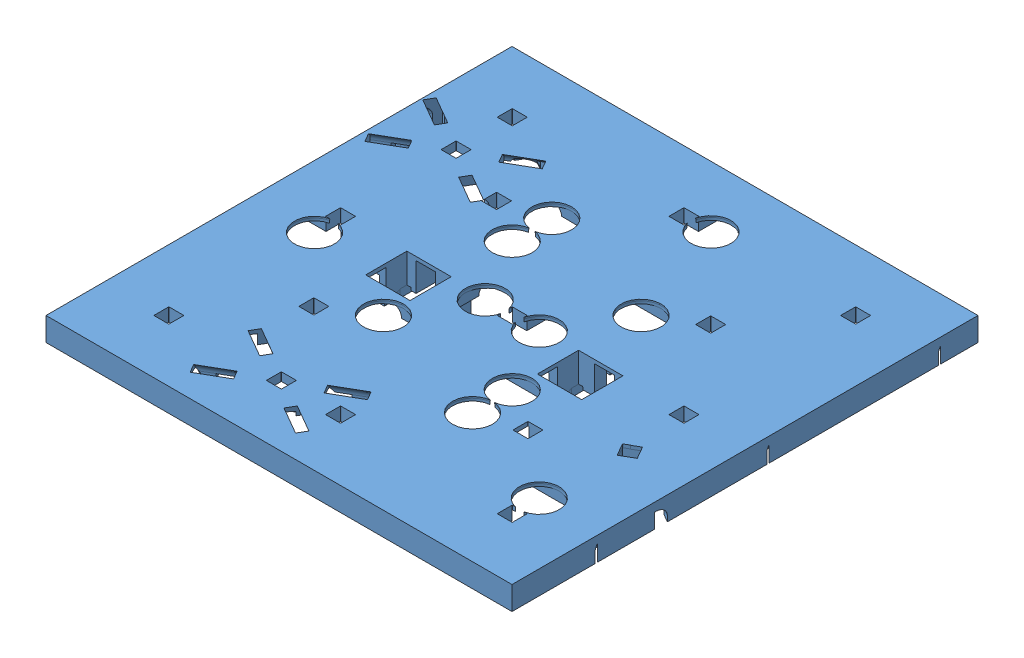
SolidWorks assembly LED_panel_assembly, configuration Default. Lengths in mm.
Overall size (94.99 7.84 94.99).
33 component instances, 7 part files, 67 mates.
Components (placement in the parent):
- Panel_Shape-1: Panel_Shape [Default] at origin size (70 7.84 70) (hidden)
- Part1^LED_panel_assembly-1: Part1^LED_panel_assembly [Default] at (0 2.5 0) x (1 0 0) z (0 1 0) size (94.99 94.99 4.78) (hidden, virtual)
- OPULENT_PCB-3: OPULENT_PCB [Default] at (-35 -1.266 -35) size (24.83 4.02 19.89) (hidden)
- OPULENT_PCB-17: OPULENT_PCB [Default] at (0 -1.266 -35) size (24.83 4.02 19.89) (hidden)
- OPULENT_PCB-18: OPULENT_PCB [Default] at (35 -1.266 -35) size (24.83 4.02 19.89) (hidden)
- OPULENT_PCB-19: OPULENT_PCB [Default] at (-35 -1.266 0) size (24.83 4.02 19.89) (hidden)
- OPULENT_PCB-20: OPULENT_PCB [Default] at (0 -1.266 0) size (24.83 4.02 19.89) (hidden)
- OPULENT_PCB-21: OPULENT_PCB [Default] at (35 -1.266 0) size (24.83 4.02 19.89) (hidden)
- OPULENT_PCB-22: OPULENT_PCB [Default] at (-35 -1.266 35) size (24.83 4.02 19.89) (hidden)
- OPULENT_PCB-23: OPULENT_PCB [Default] at (0 -1.266 35) size (24.83 4.02 19.89) (hidden)
- OPULENT_PCB-24: OPULENT_PCB [Default] at (35 -1.266 35) size (24.83 4.02 19.89) (hidden)
- Chanzon_Led-1: Chanzon_Led [Default] at (13.125 5.25 -13.125) x (0.565498 0 0.82475) z (0.82475 0 -0.565498) size (14.74 5.5 16.4) (hidden)
- Chanzon_Led-2: Chanzon_Led [Default] at (13.125 5.25 13.125) x (0.565498 0 0.82475) z (0.82475 0 -0.565498) size (14.74 5.5 16.4) (hidden)
- Chanzon_Led-3: Chanzon_Led [Default] at (-13.125 5.25 -13.125) x (0.565498 0 0.82475) z (0.82475 0 -0.565498) size (14.74 5.5 16.4) (hidden)
- Chanzon_Led-4: Chanzon_Led [Default] at (-13.125 5.25 13.125) x (0.565498 0 0.82475) z (0.82475 0 -0.565498) size (14.74 5.5 16.4) (hidden)
- Chanzon_Led-5: Chanzon_Led [Default] at (-34.8 5.25 5.51) x (0.565498 0 0.82475) z (0.82475 0 -0.565498) size (14.74 5.5 16.4) (hidden)
- Chanzon_Led-6: Chanzon_Led [Default] at (35 5.25 29.49) x (0.565498 0 0.82475) z (0.82475 0 -0.565498) size (14.74 5.5 16.4) (hidden)
- Chanzon_Led-7: Chanzon_Led [Default] at (5.51 5.25 -35) x (-0.82475 0 0.565498) z (0.565498 0 0.82475) size (14.74 5.5 16.4) (hidden)
- Chanzon_Led-8: Chanzon_Led [Default] at (5.51 5.25 0) x (0.82475 0 -0.565498) z (-0.565498 0 -0.82475) size (14.74 5.5 16.4) (hidden)
- Chanzon_Led-9: Chanzon_Led [Default] at (-13.125 5.25 -21.175) x (0.565498 0 0.82475) z (0.82475 0 -0.565498) size (14.74 5.5 16.4) (hidden)
- Chanzon_Led-10: Chanzon_Led [Default] at (13.125 5.25 21.225) x (-0.565498 0 -0.82475) z (-0.82475 0 0.565498) size (14.74 5.5 16.4) (hidden)
- OPULENT_PCB-25: OPULENT_PCB [Default] at (-21.825 -1.266 18.625) x (0 0 -1) z (1 0 0) size (24.83 4.02 19.89) (hidden)
- OPULENT_PCB-28: OPULENT_PCB [Default] at (21.825 -1.266 18.625) x (0 0 -1) z (1 0 0) size (24.83 4.02 19.89) (hidden)
- OPULENT_PCB-29: OPULENT_PCB [Default] at (21.825 -1.266 -18.625) x (0 0 -1) z (1 0 0) size (24.83 4.02 19.89) (hidden)
- OPULENT_PCB-30: OPULENT_PCB [Default] at (-21.825 -1.266 -18.625) x (0 0 -1) z (1 0 0) size (24.83 4.02 19.89) (hidden)
- Chanzon_Led-11: Chanzon_Led [Default] at (-5.51 5.25 0) x (-0.82475 0 0.565498) z (0.565498 0 0.82475) size (14.74 5.5 16.4) (hidden)
- OPULENT_PCB-31: OPULENT_PCB [Default] at (-12.0659 -0.25 35) size (24.83 4.02 19.89) (hidden)
- OPULENT_PCB-32: OPULENT_PCB [Default] at (-35 -0.25 -23.5559) size (24.83 4.02 19.89) (hidden)
- OPULENT_PCB-33: OPULENT_PCB [Default] at (35.9442 -2.282 11.9777) x (-0.5 0 -0.866025) z (0.866025 0 -0.5) size (24.83 4.02 19.89) (hidden)
- Bulb solo-1: Bulb solo [Default] at (17.5 -5.266 -4.572) x (1 0 0) z (0 -1 0) size (9.59 20.8 8.73) (hidden)
- Bulb solo-2: Bulb solo [Default] at (-17.5 -5.266 -4.572) x (1 0 0) z (0 -1 0) size (9.59 20.8 8.73) (hidden)
- Full_panel^LED_panel_assembly-1: Full_panel^LED_panel_assembly [Default] at origin size (94.99 7.84 94.99)
- Led_panel_inverted_holder-1: Led_panel_inverted_holder [Default] at origin (suppressed, hidden)
Mates (geometry in assembly coordinates):
- Parallel1: parallel: plane of Panel_Shape-1 through (0 2.5 0) normal (0 1 0); plane of Chanzon_Led-1 through (13.125 5.25 -13.125) normal (0 1 0)
- Distance6: distance = 7.4 mm: plane of Chanzon_Led-5 through (-27.6 1.75 1.51) normal (1 0 0); plane of Panel_Shape-1 through (-35 2.5 35) normal (-1 0 0)
- Parallel3: parallel: plane of Panel_Shape-1 through (-35 2.5 35) normal (-1 0 0); plane of OPULENT_PCB-3 through (-36.5 2.75 -33.5) normal (-1 0 0)
- Distance9: distance = 1.5 mm: plane of Panel_Shape-1 through (-35 2.5 35) normal (-1 0 0); plane of OPULENT_PCB-3 through (-33.5 2.75 -33.5) normal (1 0 0)
- Distance35: distance = 0.01 mm: plane of OPULENT_PCB-19 through (-36.5 2.75 1.5) normal (0 0 1); plane of Chanzon_Led-5 through (-27.6 1.75 1.51) normal (0 0 -1)
- Coincident619: coincident: plane of Chanzon_Led-1 through (13.125 5.25 -13.125) normal (0 1 0); plane of Chanzon_Led-5 through (-34.8 5.25 5.51) normal (0 1 0)
- Distance10: distance = 7.2 mm: plane of Panel_Shape-1 through (35 2.5 35) normal (1 0 0); plane of Chanzon_Led-6 through (27.8 1.75 25.49) normal (-1 0 0)
- Distance36: distance = 0.01 mm: plane of OPULENT_PCB-24 through (33.5 2.75 33.5) normal (0 0 -1); plane of Chanzon_Led-6 through (42.2 1.75 33.49) normal (0 0 1)
- Coincident620: coincident: plane of Chanzon_Led-1 through (13.125 5.25 -13.125) normal (0 1 0); plane of Chanzon_Led-6 through (35 5.25 29.49) normal (0 1 0)
- Parallel5: parallel: plane of Panel_Shape-1 through (-35 2.5 -35) normal (0 0 -1); plane of Chanzon_Led-7 through (9.51 1.75 -27.8) normal (0 0 1)
- Distance34: distance = 0.01 mm: plane of OPULENT_PCB-17 through (1.5 2.75 -33.5) normal (1 0 0); plane of Chanzon_Led-7 through (1.51 1.75 -27.8) normal (-1 0 0)
- Coincident621: coincident: plane of Chanzon_Led-1 through (13.125 5.25 -13.125) normal (0 1 0); plane of Chanzon_Led-7 through (5.51 5.25 -35) normal (0 1 0)
- Distance11: distance = 5.7 mm: plane of Chanzon_Led-7 through (9.51 1.75 -27.8) normal (0 0 1); plane of OPULENT_PCB-17 through (-1.5 2.75 -33.5) normal (0 0 1)
- Coincident26: coincident: plane of Chanzon_Led-8 through (5.51 5.25 0) normal (0 1 0); plane of Chanzon_Led-1 through (13.125 5.25 -13.125) normal (0 1 0)
- Distance12: distance = 5.7 mm: plane of Chanzon_Led-8 through (1.51 1.75 7.2) normal (0 0 1); plane of OPULENT_PCB-20 through (-1.5 2.75 1.5) normal (0 0 1)
- Distance14: distance = 17.875 mm: plane of Chanzon_Led-1 through (20.325 1.75 -17.125) normal (0 0 -1); plane of Panel_Shape-1 through (-35 2.5 -35) normal (0 0 -1)
- Distance15: distance = 14.675 mm: plane of Panel_Shape-1 through (35 2.5 35) normal (1 0 0); plane of Chanzon_Led-1 through (20.325 1.75 -17.125) normal (1 0 0)
- Distance39: distance = 0.05 mm: plane of Chanzon_Led-3 through (-5.925 1.75 -17.125) normal (0 0 -1); plane of Chanzon_Led-9 through (-5.925 1.75 -17.175) normal (0 0 1)
- Coincident40: coincident: plane of Chanzon_Led-3 through (-5.925 1.75 -17.125) normal (1 0 0); plane of Chanzon_Led-9 through (-5.925 1.75 -25.175) normal (1 0 0)
- Coincident41: coincident: plane of Chanzon_Led-9 through (-13.125 5.25 -21.175) normal (0 1 0); plane of Chanzon_Led-1 through (13.125 5.25 -13.125) normal (0 1 0)
- Coincident42: coincident: plane of Chanzon_Led-2 through (20.325 1.75 9.125) normal (1 0 0); plane of Chanzon_Led-10 through (20.325 1.75 25.225) normal (1 0 0)
- Distance40: distance = 0.1 mm: plane of Chanzon_Led-2 through (20.325 1.75 17.125) normal (0 0 1); plane of Chanzon_Led-10 through (5.925 1.75 17.225) normal (0 0 -1)
- Coincident44: coincident: plane of Chanzon_Led-10 through (13.125 5.25 21.225) normal (0 1 0); plane of Chanzon_Led-1 through (13.125 5.25 -13.125) normal (0 1 0)
- Coincident46: coincident: plane of OPULENT_PCB-25 through (-21.825 -0.25 18.625) normal (0 1 0); plane of Chanzon_Led-1 through (13.125 -0.25 -13.125) normal (0 -1 0)
- Coincident48: coincident: plane of OPULENT_PCB-28 through (21.825 -0.25 18.625) normal (0 1 0); plane of Chanzon_Led-1 through (13.125 -0.25 -13.125) normal (0 -1 0)
- Coincident49: coincident: plane of OPULENT_PCB-30 through (-20.325 2.75 -17.125) normal (0 0 1); plane of Chanzon_Led-3 through (-5.925 1.75 -17.125) normal (0 0 -1)
- Coincident50: coincident: plane of OPULENT_PCB-30 through (-21.825 -0.25 -18.625) normal (0 1 0); plane of Chanzon_Led-1 through (13.125 -0.25 -13.125) normal (0 -1 0)
- Coincident52: coincident: plane of Chanzon_Led-1 through (13.125 -0.25 -13.125) normal (0 -1 0); plane of OPULENT_PCB-29 through (21.825 -0.25 -18.625) normal (0 1 0)
- Distance32: distance = 2.75 mm: plane of Panel_Shape-1 through (0 2.5 0) normal (0 1 0); plane of Chanzon_Led-1 through (13.125 5.25 -13.125) normal (0 1 0)
- Distance38: distance = 0.01 mm: plane of OPULENT_PCB-20 through (-1.5 2.75 1.5) normal (-1 0 0); plane of Chanzon_Led-11 through (-1.51 1.75 7.2) normal (1 0 0)
- Parallel7: parallel: plane of Panel_Shape-1 through (0 2.5 0) normal (0 1 0); plane of Chanzon_Led-11 through (-5.51 5.25 0) normal (0 1 0)
- Coincident59: coincident: plane of Chanzon_Led-8 through (1.51 1.75 7.2) normal (0 0 1); plane of Chanzon_Led-11 through (-1.51 1.75 7.2) normal (0 0 1)
- Coincident559: coincident: plane of OPULENT_PCB-23 through (-1.5 2.75 36.5) normal (0 0 1); plane of OPULENT_PCB-31 through (-13.5659 3.766 36.5) normal (0 0 1)
- Coincident560: coincident: plane of OPULENT_PCB-23 through (0 -0.25 35) normal (0 1 0); plane of OPULENT_PCB-31 through (-12.0659 -0.25 35) normal (0 -1 0)
- Coincident563: coincident: plane of OPULENT_PCB-21 through (35 -1.266 0) normal (0 -1 0); plane of OPULENT_PCB-33 through (35.9442 -1.266 11.9777) normal (0 1 0)
- Coincident565: coincident: plane of OPULENT_PCB-30 through (-20.325 2.75 -17.125) normal (1 0 0); plane of Chanzon_Led-3 through (-20.325 1.75 -17.125) normal (-1 0 0)
- Coincident566: coincident: plane of Chanzon_Led-1 through (20.325 1.75 -17.125) normal (1 0 0); plane of OPULENT_PCB-29 through (20.325 2.75 -17.125) normal (-1 0 0)
- Coincident573: coincident: plane of OPULENT_PCB-3 through (-36.5 2.75 -33.5) normal (-1 0 0); plane of OPULENT_PCB-32 through (-36.5 3.766 -22.0559) normal (-1 0 0)
- Parallel9: parallel: plane of OPULENT_PCB-20 through (0 -0.25 0) normal (0 1 0); plane of Chanzon_Led-11 through (-5.51 -0.25 0) normal (0 -1 0)
- Coincident577: coincident: plane of OPULENT_PCB-20 through (0 -0.25 0) normal (0 1 0); plane of Chanzon_Led-11 through (-5.51 -0.25 0) normal (0 -1 0)
- Distance37: distance = 0.01 mm: plane of OPULENT_PCB-20 through (1.5 2.75 1.5) normal (1 0 0); plane of Chanzon_Led-8 through (1.51 1.75 -7.2) normal (-1 0 0)
- Coincident579: coincident: plane of OPULENT_PCB-32 through (-35 -0.25 -23.5559) normal (0 -1 0); plane of OPULENT_PCB-3 through (-35 -0.25 -35) normal (0 1 0)
- Coincident580: coincident: plane of OPULENT_PCB-3 through (-36.5 2.75 -33.5) normal (0 0 1); plane of OPULENT_PCB-32 through (-29.2588 0.766 -33.5) normal (0 0 -1)
- Coincident581: coincident: line of OPULENT_PCB-23 through (-10.5659 -1.266 33.4125) axis (0 1 0); plane of OPULENT_PCB-31 through (-10.5659 3.766 36.5) normal (1 0 0)
- Distance43: distance = 0.01 mm: line of OPULENT_PCB-33 through (36.4492 1.734 9.9541) axis (0 -1 0); plane of OPULENT_PCB-21 through (29.2588 -0.25 9.9441) normal (0 0 1)
- Coincident593: coincident: plane of OPULENT_PCB-3 through (-35 -0.25 -35) normal (0 1 0); plane of Chanzon_Led-1 through (13.125 -0.25 -13.125) normal (0 -1 0)
- Distance24: distance = 17.5 mm: plane of Bulb solo-1 through (17.5 -5.266 -4.572) normal (1 0 0); plane of Panel_Shape-1 through (35 2.5 35) normal (1 0 0)
- Distance26: distance = 30.428 mm: plane of Bulb solo-1 through (17.5 -5.266 -4.572) normal (0 0 1); plane of Panel_Shape-1 through (-35 2.5 -35) normal (0 0 -1)
- Distance27: distance = 4 mm: plane of OPULENT_PCB-28 through (21.825 -1.266 18.625) normal (0 -1 0); plane of Bulb solo-1 through (17.5 -5.266 -4.572) normal (0 -1 0)
- Distance29: distance = 1.5 mm: plane of OPULENT_PCB-3 through (-36.5 2.75 -36.5) normal (0 0 -1); plane of Panel_Shape-1 through (-35 2.5 -35) normal (0 0 -1)
- Coincident605: coincident: plane of OPULENT_PCB-28 through (23.325 2.75 17.125) normal (0 0 -1); plane of Chanzon_Led-2 through (20.325 1.75 17.125) normal (0 0 1)
- Coincident606: coincident: plane of Chanzon_Led-10 through (20.325 1.75 25.225) normal (1 0 0); plane of OPULENT_PCB-28 through (20.325 2.75 20.125) normal (-1 0 0)
- Coincident612: coincident: plane of Chanzon_Led-1 through (20.325 1.75 -17.125) normal (0 0 -1); plane of OPULENT_PCB-29 through (23.325 2.75 -17.125) normal (0 0 1)
- InPlace10: in place: plane of ? through (82.8743 -37.325 98.595) normal (-0.15208 0.988368 -0.001149); plane of ? through (7.5443 -49.0305 0.057) normal (-0.15208 0.988368 -0.001149); moOrthogonalPlaneRef_w of ? through (82.8743 -37.325 98.595) normal (-0.15208 0.988368 -0.001149); plane of ? through (7.5443 -49.0305 0.057) normal (0 -0.001163 -0.999999); plane of ? through (82.8743 -37.325 98.595) normal (-0.15208 0.988368 -0.001149); plane of ? through (7.5443 -49.0305 0.057) normal (0.988368 0.15208 -0.000177); plane of OPULENT_PCB-22 through (-35 -0.25 35) normal (0 1 0); unknown of ?
- Coincident637: coincident: plane of OPULENT_PCB-22; plane of ?
- Coincident638: coincident: moOrthogonalPlaneRef_w of OPULENT_PCB-22; plane of ? through (-35 -0.25 35) normal (0 0 -1)
- Coincident639: coincident: moOrthogonalPlaneRef_w of OPULENT_PCB-22; plane of ? through (-35 -0.25 35) normal (1 0 0)
- InPlace11: in place: plane of ? through (87.5193 -34.1381 49.3557) normal (-0.15208 0.988368 -0.001149); plane of ? through (7.1641 -46.5596 0.0541) normal (-0.15208 0.988368 -0.001149); plane of ? through (87.5193 -34.1381 49.3557) normal (-0.15208 0.988368 -0.001149); plane of ? through (7.1641 -46.5596 0.0541) normal (0 -0.001163 -0.999999); plane of ? through (87.5193 -34.1381 49.3557) normal (-0.15208 0.988368 -0.001149); plane of ? through (7.1641 -46.5596 0.0541) normal (0.988368 0.15208 -0.000177); plane of ? through (0 2.5 0) normal (0 1 0); unknown of Part1^LED_panel_assembly-1
- Coincident613: coincident: plane of Panel_Shape-1; plane of Part1^LED_panel_assembly-1
- Coincident614: coincident: moOrthogonalPlaneRef_w of Panel_Shape-1; plane of Part1^LED_panel_assembly-1 through (0 2.5 0) normal (0 0 -1)
- Coincident615: coincident: moOrthogonalPlaneRef_w of Panel_Shape-1 through (-61.7382 0 2.5) axis (0 -1 0); plane of Part1^LED_panel_assembly-1 through (0 2.5 0) normal (1 0 0)
- Coincident613: coordinate: point of ?
- Coincident614: coordinate: unknown of ?
- Parallel10: parallel: plane of OPULENT_PCB-21 through (29.2588 -0.25 9.9441) normal (0 0 1); plane of OPULENT_PCB-33 through (30.2029 -1.266 21.9218) normal (0 0 1)
- Coincident616: coordinate: unknown of ?
- Coincident622: coincident: plane of Chanzon_Led-4 through (-5.925 1.75 17.125) normal (0 0 1); plane of OPULENT_PCB-25 through (-20.325 2.75 17.125) normal (0 0 -1)
- Coincident623: coincident: plane of Chanzon_Led-4 through (-20.325 1.75 9.125) normal (-1 0 0); plane of OPULENT_PCB-25 through (-20.325 2.75 20.125) normal (1 0 0)
